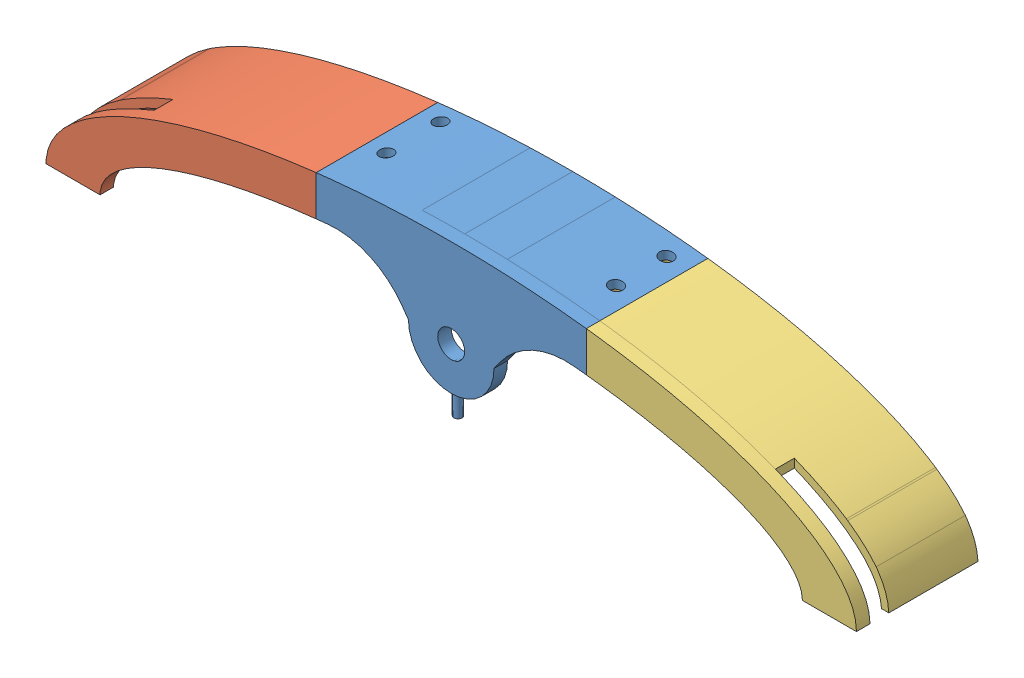
SolidWorks assembly moustache, configuration Défaut. Lengths in mm.
Overall size (300 57 45).
3 component instances, 3 part files, 6 mates.
Components (placement in the parent):
- centre-moustache-1: centre-moustache [Défaut] at (120.8089 -27.9707 76.148) size (100 57 45)
- left-moustache-1: left-moustache [Défaut] at (120.8089 -27.9707 76.148) size (115 47.14 45)
- right-moustache-1: right-moustache [Défaut] at (120.8089 -27.9707 76.148) size (115 47.14 45)
Mates (geometry in assembly coordinates):
- Parallèle1: parallel anti-aligned: plane of left-moustache-1 through (70.8089 -27.9707 76.148) normal (1 0 0); plane of centre-moustache-1 through (70.8089 -27.9707 76.148) normal (-1 0 0)
- Coaxiale1: concentric aligned: cylinder of centre-moustache-1 through (78.3089 22.0308 62.648) axis (0 -1 0) radius 2.5; cylinder of left-moustache-1 through (78.3089 22.0308 62.648) axis (0 -1 0) radius 2.5
- Coïncidente1: coincident: point of centre-moustache-1; point of left-moustache-1
- Coïncidente2: coincident anti-aligned: plane of centre-moustache-1 through (170.8089 -27.9707 76.148) normal (1 0 0); plane of right-moustache-1 through (170.8089 -27.9707 76.148) normal (-1 0 0)
- Coaxiale2: concentric aligned: cylinder of centre-moustache-1 through (163.3089 22.0308 62.648) axis (0 -1 0) radius 2.5; cylinder of right-moustache-1 through (163.3089 22.0308 62.648) axis (0 -1 0) radius 2.5
- Coïncidente3: coincident: point of centre-moustache-1; point of right-moustache-1
